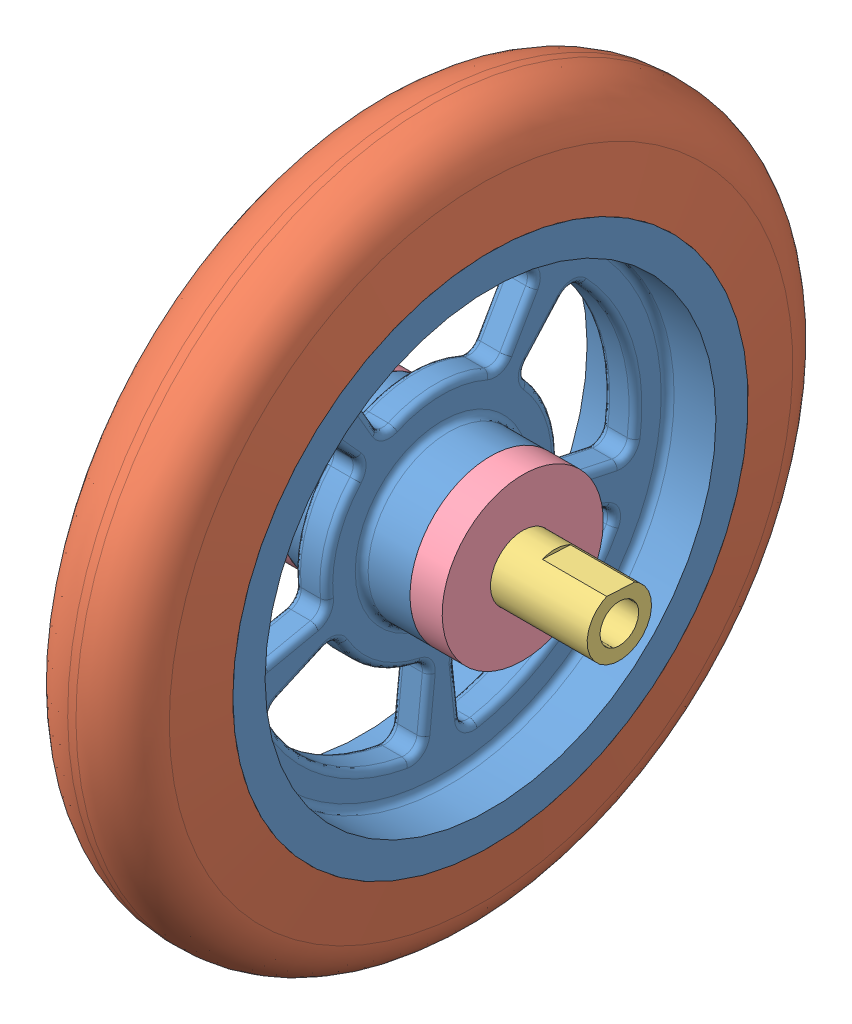
SolidWorks assembly Wheel and Axel.2, configuration Default. Lengths in mm.
Overall size (60 115.31 115.31).
5 component instances, 4 part files, 7 mates.
Components (placement in the parent):
- Wheel.SLDPART-1: Wheel.SLDPART [Default] at (23.415 45.1517 62.4965) size (20 80 80)
- Tire.SLDPART-1: Tire.SLDPART [Default] at (23.415 45.1517 62.4965) x (1 0 0) z (0 -0.049481 0.998775) size (20 110 110)
- Axel.SLDPART-1: Axel.SLDPART [Default] at (23.415 45.1517 62.4965) x (0 -0.050219 -0.998738) z (1 0 0) size (10 10 60)
- Washer.SLDPART-1: Washer.SLDPART [Default] at (8.415 45.1517 62.4965) x (0 -0.153708 -0.988116) z (0 -0.988116 0.153708) size (25 5 25)
- Washer.SLDPART-2: Washer.SLDPART [Default] at (38.415 45.1517 62.4965) x (0 0.906189 0.422872) z (0 -0.422872 0.906189) size (25 5 25)
Mates (geometry in assembly coordinates):
- Coincident1: coincident aligned: circle of Wheel.SLDPART-1; circle of Tire.SLDPART-1
- Coincident5: coincident aligned: plane of Wheel.SLDPART-1 through (23.415 45.1517 62.4965) normal (1 0 0); plane of Axel.SLDPART-1 through (23.415 45.1517 62.4965) normal (1 0 0)
- Concentric1: concentric anti-aligned: cylinder of Axel.SLDPART-1 through (53.415 45.1517 62.4965) axis (-1 0 0) radius 5; cylinder of Washer.SLDPART-2 through (33.415 45.1517 62.4965) axis (1 0 0) radius 5
- Coincident15: coincident anti-aligned: plane of Wheel.SLDPART-1 through (33.415 45.1517 49.9965) normal (1 0 0); plane of Washer.SLDPART-2 through (33.415 45.1517 62.4965) normal (-1 0 0)
- Concentric2: concentric aligned: cylinder of Wheel.SLDPART-1 through (23.415 45.1517 62.4965) axis (-1 0 0) radius 5; cylinder of Axel.SLDPART-1 through (53.415 45.1517 62.4965) axis (-1 0 0) radius 5
- Coincident16: coincident anti-aligned: plane of Wheel.SLDPART-1 through (13.415 45.1517 49.9965) normal (-1 0 0); plane of Washer.SLDPART-1 through (13.415 45.1517 62.4965) normal (1 0 0)
- Concentric3: concentric aligned: cylinder of Axel.SLDPART-1 through (53.415 45.1517 62.4965) axis (-1 0 0) radius 5; cylinder of Washer.SLDPART-1 through (13.415 45.1517 62.4965) axis (-1 0 0) radius 5
